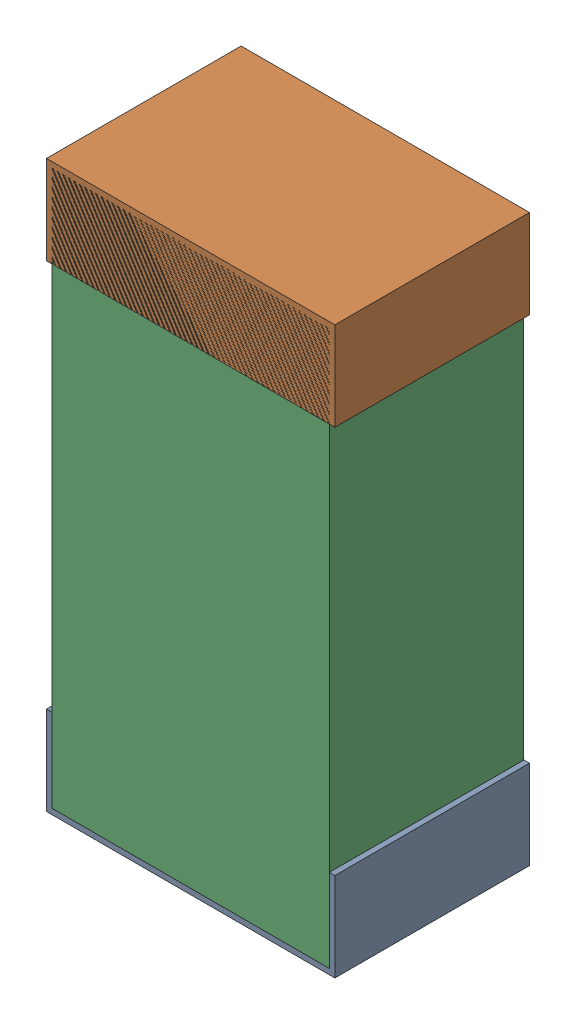
SolidWorks assembly C50, configuration Default. Lengths in mm.
Overall size (0.52 1.02 0.35).
6 component instances, 2 part files, 0 mates.
Components (placement in the parent):
- 870941120-1: 870941120 [Default] at (12.4452 36.7496 -1.9516) size (0.52 0.16 0.35)
  - Extruded_3-1: Extruded_3 [Default] at origin size (0.52 0.16 0.35)
- 870941120-2: 870941120 [Default] at (12.4452 37.6096 -1.9516) size (0.52 0.16 0.35)
  - Extruded_3-1: Extruded_3 [Default] at origin size (0.52 0.16 0.35)
- 870941280-1: 870941280 [Default] at (12.4452 37.1796 -1.9506) size (0.5 1 0.35)
  - Extruded_4-1: Extruded_4 [Default] at origin size (0.5 1 0.35)
